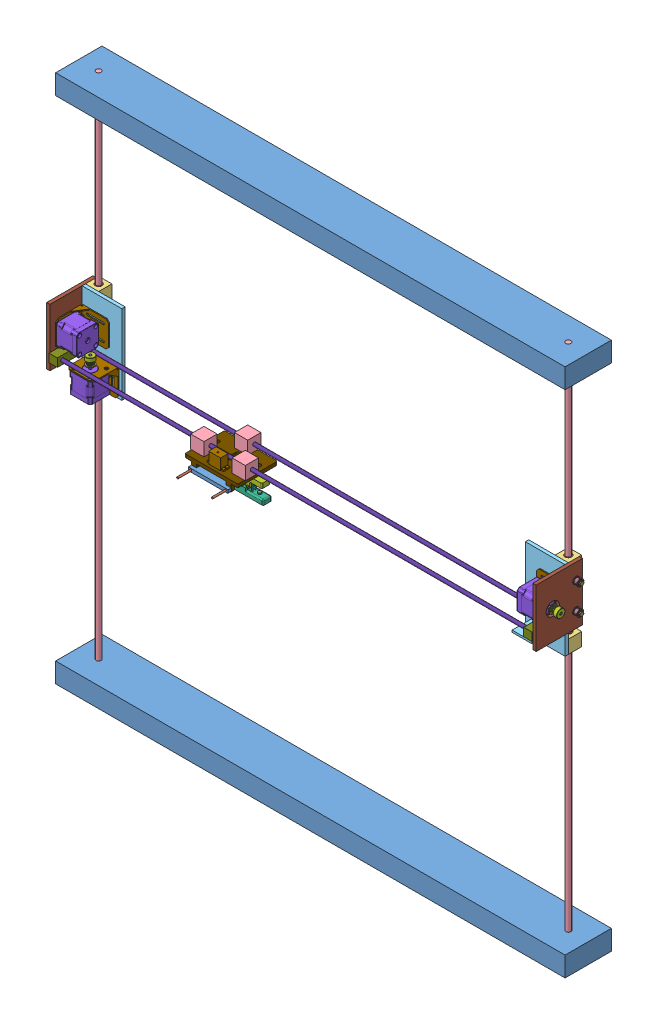
SolidWorks assembly Final Assembly, configuration Default. Lengths in mm.
Overall size (977.9 1016 174.63).
108 component instances, 28 part files, 72 mates.
Components (placement in the parent):
- Wood support-1: Wood support [Default] at (-151.6885 381.3846 556.984) size (977.9 38.1 88.9)
- Wood support-3: Wood support [Default] at (-151.6885 1397.3846 645.884) x (1 0 0) z (0 0 -1) size (977.9 38.1 88.9)
- Wood block w fitting-1: Wood block w fitting [Default] at (-133.7789 1054.3667 617.7695) x (0 0 -1) z (0 -1 0) size (25.4 25.4 25.4)
  - Bronze fitting-1: Bronze fitting [Default] at (16.3355 20.1904 11.168) size (12.7 12.7 25.4)
  - Wood block-1: Wood block [Default] at (3.6355 7.4904 11.168) size (25.4 25.4 25.4)
- Wood block w fitting-2: Wood block w fitting [Default] at (-133.7789 927.3667 617.7695) x (0 0 -1) z (0 -1 0) size (25.4 25.4 25.4)
  - Bronze fitting-1: Bronze fitting [Default] at (16.3355 20.1904 11.168) size (12.7 12.7 25.4)
  - Wood block-1: Wood block [Default] at (3.6355 7.4904 11.168) size (25.4 25.4 25.4)
- Wood block w fitting-3: Wood block w fitting [Default] at (808.3019 1054.3667 585.0985) x (0 0 1) z (0 -1 0) size (25.4 25.4 25.4)
  - Bronze fitting-1: Bronze fitting [Default] at (16.3355 20.1904 11.168) size (12.7 12.7 25.4)
  - Wood block-1: Wood block [Default] at (3.6355 7.4904 11.168) size (25.4 25.4 25.4)
- Wood block w fitting-4: Wood block w fitting [Default] at (808.3019 927.3667 585.0985) x (0 0 1) z (0 -1 0) size (25.4 25.4 25.4)
  - Bronze fitting-1: Bronze fitting [Default] at (16.3355 20.1904 11.168) size (12.7 12.7 25.4)
  - Wood block-1: Wood block [Default] at (3.6355 7.4904 11.168) size (25.4 25.4 25.4)
- Steel Rod-1: Steel Rod [Default] at (-113.5885 1397.3846 601.434) x (0.921856 0 -0.387532) z (0 -1 0) size (9.53 9.53 1016)
- Steel Rod-2: Steel Rod [Default] at (788.1115 1397.3846 601.434) x (-0.979084 0 0.203454) z (0 -1 0) size (9.53 9.53 1016)
- Support piece 2-1: Support piece 2 [Default] at (-88.1885 966.9987 614.134) x (0 -1 0) z (-1 0 0) size (152.4 6.35 76.2)
- Assem1-1: Assem1 [Default] at (-363.1535 858.375 468.4599) x (0 1 0) z (1 0 0) size (110.49 88.9 75.3)
  - Stepper Motor Assembly-1: Stepper Motor Assembly [Default] at (-2.6319 57.0939 61.9281) size (50 51.29 75.3)
    - Screw-1: Screw [Default] at (147.7106 140.4303 199.9369) x (-0.047434 -0.998874 0) z (0.998874 -0.047434 0) size (7 25.04 7)
    - GT2_Pulley20_Teeth.stp-1: GT2_Pulley20_Teeth.stp [Default] at (132.2106 125.0707 168.6369) x (-0.679392 0.733775 0) z (0 0 -1) size (16 16 16)
    - NEMA_17_Stepper_Motor.step-1: NEMA_17_Stepper_Motor.step [Default] at (136.9106 140.0707 -883.0631) size (42.3 42.3 63.3)
    - Nema17_Mounting_Bracket-1: Nema17_Mounting_Bracket [Default] at (157.2106 94.9303 174.9369) x (0 0 1) z (-1 0 0) size (53 51 50)
    - Screw-2: Screw [Default] at (116.7106 109.4303 199.8369) x (1 0 0) z (0 1 0) size (7 25.04 7)
    - Screw.step-2: Screw.step [Default] at (147.7106 109.4303 199.9369) x (1 0 0) z (0 1 0) size (7 25.04 7)
    - Screw.step-3: Screw.step [Default] at (116.7106 140.5707 199.9369) x (-1 0 0) z (0 -1 0) size (7 25.04 7)
  - Support Piece-1: Support Piece [Default] at (184.8237 213.7741 230.515) x (-1 0 0) z (0 1 0) size (110.49 6.35 88.9)
  - Hexagonal Bolt M4-25-1: Hexagonal Bolt M4-25 [Default] at (154.9787 137.5741 221.761) x (0 0 1) z (-0.984688 0.174326 0) size (22.54 7 8.08)
    - Hexagonal Bolt M4-25-1: Hexagonal Bolt M4-25 [Default] at origin size (28.05 7 8.08)
  - GT2_Pulley_No_Teeth.step-1: GT2_Pulley_No_Teeth.step [Default] at (153.5262 139.0817 213.265) x (-0.999997 0.002516 0) z (0 0 1) size (13 13 8.5)
  - GT2_Pulley_No_Teeth.step-2: GT2_Pulley_No_Teeth.step [Default] at (102.2066 138.2764 239.011) x (-0.414322 0.91013 0) z (0 0 -1) size (13 13 8.5)
  - Hexagonal Bolt M4-25-4: Hexagonal Bolt M4-25 [Default] at (104.1787 137.5741 221.507) x (0 0 1) z (-0.959769 0.280791 0) size (22.54 7 8.08)
    - Hexagonal Bolt M4-25-1: Hexagonal Bolt M4-25 [Default] at origin size (28.05 7 8.08)
  - Washer-1: Washer [Default] at (104.1787 137.5741 230.515) x (1 0 0) z (0 1 0) size (9.53 0.25 9.53)
  - Washer-2: Washer [Default] at (154.9787 137.5741 230.515) x (1 0 0) z (0 1 0) size (9.53 0.25 9.53)
  - Washer-3: Washer [Default] at (104.1787 137.5741 221.507) x (0.130919 0.991393 0) z (0.991393 -0.130919 0) size (9.53 0.25 9.53)
  - Washer-4: Washer [Default] at (154.9787 137.5741 221.761) x (0.849495 -0.527597 0) z (-0.527597 -0.849495 0) size (9.53 0.25 9.53)
  - Washer-5: Washer [Default] at (104.1787 137.5741 237.119) x (0.704272 0.70993 0) z (-0.70993 0.704272 0) size (9.53 0.25 9.53)
  - Washer-6: Washer [Default] at (154.9787 137.5741 237.119) x (1 0 0) z (0 1 0) size (9.53 0.25 9.53)
  - Hexagonal Nut M4-1: Hexagonal Nut M4 [Default] at (154.99 137.5786 237.119) x (0.949988 -0.312286 0) z (-0.312286 -0.949988 0) size (7 3.45 8.08)
    - Hexagonal Nut M4-1: Hexagonal Nut M4 [Default] x (0 -1 0) z (-1 0 0) size (3.45 8.08 7)
  - Hexagonal Nut M4-2: Hexagonal Nut M4 [Default] at (104.196 137.5251 237.119) x (0.955479 -0.29506 0) z (-0.29506 -0.955479 0) size (7 3.45 8.08)
    - Hexagonal Nut M4-1: Hexagonal Nut M4 [Default] x (0 -1 0) z (-1 0 0) size (3.45 8.08 7)
- Stepper Motor Assembly-1: Stepper Motor Assembly [Default] at (-212.6756 1118.7356 525.5537) x (1 0 0) z (0 -1 0) size (50 51.29 75.3)
  - Screw-1: Screw [Default] at (147.7106 140.4303 199.9369) x (-0.047434 -0.998874 0) z (0.998874 -0.047434 0) size (7 25.04 7)
  - GT2_Pulley20_Teeth.stp-1: GT2_Pulley20_Teeth.stp [Default] at (132.2106 125.0707 168.6369) x (-0.679392 0.733775 0) z (0 0 -1) size (16 16 16)
  - NEMA_17_Stepper_Motor.step-1: NEMA_17_Stepper_Motor.step [Default] at (136.9106 140.0707 -883.0631) size (42.3 42.3 63.3)
  - Nema17_Mounting_Bracket-1: Nema17_Mounting_Bracket [Default] at (157.2106 94.9303 174.9369) x (0 0 1) z (-1 0 0) size (53 51 50)
  - Screw-2: Screw [Default] at (116.7106 109.4303 199.8369) x (1 0 0) z (0 1 0) size (7 25.04 7)
  - Screw.step-2: Screw.step [Default] at (147.7106 109.4303 199.9369) x (1 0 0) z (0 1 0) size (7 25.04 7)
  - Screw.step-3: Screw.step [Default] at (116.7106 140.5707 199.9369) x (-1 0 0) z (0 -1 0) size (7 25.04 7)
- Assem1-2: Assem1 [Default] at (1037.6765 1117.5324 468.4599) x (0 -1 0) z (-1 0 0) size (110.49 88.9 75.3)
  - Stepper Motor Assembly-1: Stepper Motor Assembly [Default] at (-2.6319 57.0939 61.9281) size (50 51.29 75.3)
    - Screw-1: Screw [Default] at (147.7106 140.4303 199.9369) x (-0.047434 -0.998874 0) z (0.998874 -0.047434 0) size (7 25.04 7)
    - GT2_Pulley20_Teeth.stp-1: GT2_Pulley20_Teeth.stp [Default] at (132.2106 125.0707 168.6369) x (-0.679392 0.733775 0) z (0 0 -1) size (16 16 16)
    - NEMA_17_Stepper_Motor.step-1: NEMA_17_Stepper_Motor.step [Default] at (136.9106 140.0707 -883.0631) size (42.3 42.3 63.3)
    - Nema17_Mounting_Bracket-1: Nema17_Mounting_Bracket [Default] at (157.2106 94.9303 174.9369) x (0 0 1) z (-1 0 0) size (53 51 50)
    - Screw-2: Screw [Default] at (116.7106 109.4303 199.8369) x (1 0 0) z (0 1 0) size (7 25.04 7)
    - Screw.step-2: Screw.step [Default] at (147.7106 109.4303 199.9369) x (1 0 0) z (0 1 0) size (7 25.04 7)
    - Screw.step-3: Screw.step [Default] at (116.7106 140.5707 199.9369) x (-1 0 0) z (0 -1 0) size (7 25.04 7)
  - Support Piece-1: Support Piece [Default] at (184.8237 213.7741 230.515) x (-1 0 0) z (0 1 0) size (110.49 6.35 88.9)
  - Hexagonal Bolt M4-25-1: Hexagonal Bolt M4-25 [Default] at (154.9787 137.5741 221.761) x (0 0 1) z (-0.984688 0.174326 0) size (22.54 7 8.08)
    - Hexagonal Bolt M4-25-1: Hexagonal Bolt M4-25 [Default] at origin size (28.05 7 8.08)
  - GT2_Pulley_No_Teeth.step-1: GT2_Pulley_No_Teeth.step [Default] at (153.5262 139.0817 213.265) x (-0.999997 0.002516 0) z (0 0 1) size (13 13 8.5)
  - GT2_Pulley_No_Teeth.step-2: GT2_Pulley_No_Teeth.step [Default] at (102.2066 138.2764 239.011) x (-0.414322 0.91013 0) z (0 0 -1) size (13 13 8.5)
  - Hexagonal Bolt M4-25-4: Hexagonal Bolt M4-25 [Default] at (104.1787 137.5741 221.507) x (0 0 1) z (-0.959769 0.280791 0) size (22.54 7 8.08)
    - Hexagonal Bolt M4-25-1: Hexagonal Bolt M4-25 [Default] at origin size (28.05 7 8.08)
  - Washer-1: Washer [Default] at (104.1787 137.5741 230.515) x (1 0 0) z (0 1 0) size (9.53 0.25 9.53)
  - Washer-2: Washer [Default] at (154.9787 137.5741 230.515) x (1 0 0) z (0 1 0) size (9.53 0.25 9.53)
  - Washer-3: Washer [Default] at (104.1787 137.5741 221.507) x (0.130919 0.991393 0) z (0.991393 -0.130919 0) size (9.53 0.25 9.53)
  - Washer-4: Washer [Default] at (154.9787 137.5741 221.761) x (0.849495 -0.527597 0) z (-0.527597 -0.849495 0) size (9.53 0.25 9.53)
  - Washer-5: Washer [Default] at (104.1787 137.5741 237.119) x (0.704272 0.70993 0) z (-0.70993 0.704272 0) size (9.53 0.25 9.53)
  - Washer-6: Washer [Default] at (154.9787 137.5741 237.119) x (1 0 0) z (0 1 0) size (9.53 0.25 9.53)
  - Hexagonal Nut M4-1: Hexagonal Nut M4 [Default] at (154.99 137.5786 237.119) x (0.949988 -0.312286 0) z (-0.312286 -0.949988 0) size (7 3.45 8.08)
    - Hexagonal Nut M4-1: Hexagonal Nut M4 [Default] x (0 -1 0) z (-1 0 0) size (3.45 8.08 7)
  - Hexagonal Nut M4-2: Hexagonal Nut M4 [Default] at (104.196 137.5251 237.119) x (0.955479 -0.29506 0) z (-0.29506 -0.955479 0) size (7 3.45 8.08)
    - Hexagonal Nut M4-1: Hexagonal Nut M4 [Default] x (0 -1 0) z (-1 0 0) size (3.45 8.08 7)
- Support piece 2-2: Support piece 2 [Default] at (762.7115 966.9987 614.134) x (0 -1 0) z (-1 0 0) size (152.4 6.35 76.2)
- Wood block 2-1: Wood block 2 [Default] at (-118.351 955.0162 620.484) x (0 1 0) z (1 0 0) size (15.88 63.5 15.88)
- Wood block 2-2: Wood block 2 [Default] at (792.874 955.0162 620.484) x (0 -1 0) z (-1 0 0) size (15.88 63.5 15.88)
- Small Steel Rod-1: Small Steel Rod [Default] at (794.4615 955.0162 674.459) x (0 0.1575 0.987519) z (-1 0 0) size (6.35 6.35 914.4)
- Small Steel Rod-2: Small Steel Rod [Default] at (794.4615 955.0162 630.009) x (0 -0.084822 0.996396) z (-1 0 0) size (6.35 6.35 914.4)
- Drawing Mount Assembly-1: Drawing Mount Assembly [Default] at (161.5337 986.3363 732.2531) x (1 0 0) z (0 0 -1) size (101.6 22.23 107.95)
  - Drawing Mount-1: Drawing Mount [Default] at (39.6439 44.0201 83.1941) size (101.6 21.18 76.2)
  - Drawing mount 2-1: Drawing mount 2 [Default] at (39.7074 56.7201 62.1343) size (76.2 9.53 69.85)
  - 0.125 Dowel pin-1: 0.125 Dowel pin [Default] at (6.3064 59.8951 0.6441) x (0.801473 -0.598031 0) z (0 0 1) size (3.17 3.17 101.6)
  - 0.125 Dowel pin-2: 0.125 Dowel pin [Default] at (72.9814 59.8951 0.6441) x (0.816688 0.577079 0) z (0 0 1) size (3.17 3.17 101.6)
  - Spring-1: Spring [Default] at (6.3064 59.8951 38.9981) x (0.94588 -0.324516 0) z (-0.324516 -0.94588 0) size (3.43 38.61 3.96)
  - Spring-2: Spring [Default] at (72.9814 59.8951 38.9981) x (-0.31762 -0.948218 0) z (-0.948218 0.31762 0) size (3.43 38.61 3.96)
- Wood Support 3-1: Wood Support 3 [Default] at (161.524 955.0162 661.759) x (1 0 0) z (0 -1 0) size (25.4 25.4 31.75)
- Wood Support 3-2: Wood Support 3 [Default] at (240.978 955.0162 661.759) x (1 0 0) z (0 -1 0) size (25.4 25.4 31.75)
- Wood Support 3-3: Wood Support 3 [Default] at (201.1154 955.0162 617.309) x (1 0 0) z (0 -1 0) size (25.4 25.4 31.75)
- Pulley Support-1: Pulley Support [Default] at (760.8789 917.7735 618.5095) size (38.1 22.54 63.5)
  - Wood support 4-1: Wood support 4 [Default] at (1.8326 25.4952 65.4745) size (38.1 3.81 63.5)
  - Hexagonal Bolt M4-25-1: Hexagonal Bolt M4-25 [Default] at (21.0153 38.3132 36.8995) x (0 -1 0) z (-0.728918 0 0.684602) size (22.54 7 8.08)
    - Hexagonal Bolt M4-25-1: Hexagonal Bolt M4-25 [Default] at origin size (28.05 7 8.08)
  - Washer-1: Washer [Default] at (21.0153 38.3132 36.8995) x (-0.092668 0 -0.995697) z (-0.995697 0 0.092668) size (9.53 0.25 9.53)
  - Washer-2: Washer [Default] at (21.0153 25.2412 36.8995) x (-0.891041 0 -0.453923) z (0.453923 0 -0.891041) size (9.53 0.25 9.53)
  - Hexagonal Nut M4-1: Hexagonal Nut M4 [Default] at (21.0153 25.2412 36.8995) x (-0.955003 0 0.296596) z (0.296596 0 0.955003) size (7 3.45 8.08)
    - Hexagonal Nut M4-1: Hexagonal Nut M4 [Default] x (0 -1 0) z (-1 0 0) size (3.45 8.08 7)
  - GT2_Pulley_No_Teeth.step-1: GT2_Pulley_No_Teeth.step [Default] at (21.373 20.8092 34.8369) x (-0.588948 0 -0.808171) z (0 1 0) size (13 13 8.5)
  - Washer-3: Washer [Default] at (21.0153 29.3052 36.8995) x (-0.288637 0 0.957438) z (-0.957438 0 -0.288637) size (9.53 0.25 9.53)
- Clamp Assembly-1: Clamp Assembly [Default] at (188.3473 857.3342 582.5233) size (72.31 35.56 16.51)
  - Clamp 1-1: Clamp 1 [Default] at (-3.6913 33.5471 71.2954) size (69.85 21.59 16.51)
  - Clamp 2-1: Clamp 2 [Default] at (-6.1562 56.4071 54.7854) x (1 0 0) z (0 0 -1) size (69.85 21.59 16.51)
  - Clamp pin-1: Clamp pin [Default] at (36.5419 44.9771 54.7854) size (3.81 3.81 16.51)
- MG90S (1)-3: MG90S (1) [Défaut] at (213.4076 963.7162 694.409) x (-1 0 0) z (0 0 1) size (31.8 32.7 14.6)
- SM Arm-1: SM Arm [Default] at (206.1576 934.3162 687.159) x (-0.004706 0 0.999989) z (0 -1 0) size (7 22 7)
Mates (geometry in assembly coordinates):
- Concentric1: concentric anti-aligned: circle of Wood support-1; circle of Wood support-3
- Parallel1: parallel aligned: plane of Wood support-1 through (-151.6885 381.3846 645.884) normal (0 0 1); plane of Wood support-3 through (-151.6885 1397.3846 645.884) normal (0 0 1)
- Concentric4: concentric aligned: circle of Wood support-3; circle of Steel Rod-2
- Concentric5: concentric aligned: cylinder of Wood block w fitting-3/Bronze fitting-1 through (788.1115 1017.7987 601.434) axis (0 1 0) radius 4.7625; cylinder of Steel Rod-2 through (788.1115 381.3846 601.434) axis (0 1 0) radius 4.7625
- Concentric6: concentric aligned: cylinder of Wood block w fitting-4/Bronze fitting-1 through (788.1115 890.7987 601.434) axis (0 1 0) radius 4.7625; cylinder of Steel Rod-2 through (788.1115 381.3846 601.434) axis (0 1 0) radius 4.7625
- Concentric7: concentric aligned: circle of Wood support-3; circle of Steel Rod-1
- Concentric8: concentric aligned: cylinder of Wood block w fitting-1/Bronze fitting-1 through (-113.5885 1017.7987 601.434) axis (0 1 0) radius 4.7625; cylinder of Steel Rod-1 through (-113.5885 381.3846 601.434) axis (0 1 0) radius 4.7625
- Concentric9: concentric aligned: cylinder of Wood block w fitting-2/Bronze fitting-1 through (-113.5885 890.7987 601.434) axis (0 1 0) radius 4.7625; cylinder of Steel Rod-1 through (-113.5885 381.3846 601.434) axis (0 1 0) radius 4.7625
- Parallel8: parallel aligned: plane of Wood block w fitting-1/Wood block-1 through (-100.8885 1017.7987 614.134) normal (1 0 0); plane of Wood block w fitting-2/Wood block-1 through (-100.8885 890.7987 614.134) normal (1 0 0)
- Parallel9: parallel aligned: plane of Wood block w fitting-3/Wood block-1 through (775.4115 1017.7987 588.734) normal (-1 0 0); plane of Wood block w fitting-4/Wood block-1 through (775.4115 890.7987 588.734) normal (-1 0 0)
- Coincident27: coincident aligned: plane of Wood support-3 through (-151.6885 1397.3846 556.984) normal (0 1 0); plane of Steel Rod-2 through (788.1115 1397.3846 601.434) normal (0 1 0)
- Coincident28: coincident aligned: plane of Wood support-3 through (-151.6885 1397.3846 556.984) normal (0 1 0); plane of Steel Rod-1 through (-113.5885 1397.3846 601.434) normal (0 1 0)
- Coincident29: coincident aligned: plane of Wood support-1 through (-151.6885 381.3846 645.884) normal (0 -1 0); plane of Steel Rod-1 through (-113.5885 381.3846 601.434) normal (0 -1 0)
- Coincident31: coincident anti-aligned: plane of Wood block w fitting-1/Wood block-1 through (-126.2885 1017.7987 614.134) normal (0 0 1); plane of Support piece 2-1 through (-88.1885 966.9987 614.134) normal (0 0 -1)
- Coincident32: coincident anti-aligned: plane of Wood block w fitting-2/Wood block-1 through (-126.2885 890.7987 614.134) normal (0 0 1); plane of Support piece 2-1 through (-88.1885 966.9987 614.134) normal (0 0 -1)
- Coincident33: coincident aligned: line of Wood block w fitting-1/Wood block-1 through (-100.8885 1043.1987 614.134) axis (-1 0 0); line of Support piece 2-1 through (-50.0885 1043.1987 614.134) axis (-1 0 0)
- Parallel13: parallel aligned: line of Wood block w fitting-1/Wood block-1 through (-100.8885 1017.7987 614.134) axis (0 1 0); line of Support piece 2-1 through (-50.0885 890.7987 620.484) axis (0 1 0)
- Parallel14: parallel anti-aligned: line of Wood block w fitting-2/Wood block-1 through (-100.8885 890.7987 614.134) axis (-1 0 0); line of Support piece 2-1 through (-126.2885 890.7987 620.484) axis (1 0 0)
- Coincident36: coincident anti-aligned: line of Wood block w fitting-2/Wood block-1 through (-100.8885 890.7987 614.134) axis (-1 0 0); line of Support piece 2-1 through (-126.2885 890.7987 614.134) axis (1 0 0)
- Parallel18: parallel aligned: plane of Wood support-3 through (-151.6885 1397.3846 645.884) normal (0 0 1); plane of Support piece 2-1 through (-88.1885 966.9987 620.484) normal (0 0 1)
- Coincident49: coincident anti-aligned: plane of Support piece 2-1 through (-88.1885 966.9987 620.484) normal (0 0 1); plane of Assem1-1/Stepper Motor Assembly-1/Nema17_Mounting_Bracket-1 through (-73.2885 962.9537 620.484) normal (0 0 -1)
- Coincident51: coincident anti-aligned: plane of Support piece 2-1 through (-126.2885 890.7987 620.484) normal (-1 0 0); plane of Assem1-1/Support Piece-1 through (-126.2885 1043.1987 682.234) normal (1 0 0)
- Parallel19: parallel anti-aligned: plane of Support piece 2-1 through (-88.1885 966.9987 620.484) normal (0 0 1); plane of Stepper Motor Assembly-1/Nema17_Mounting_Bracket-1 through (-105.465 890.7987 620.484) normal (0 0 -1)
- Parallel20: parallel aligned: plane of Support piece 2-1 through (-126.2885 890.7987 620.484) normal (0 -1 0); plane of Stepper Motor Assembly-1/Nema17_Mounting_Bracket-1 through (-105.465 890.7987 622.484) normal (0 -1 0)
- Parallel21: parallel aligned: plane of Support piece 2-1 through (-126.2885 890.7987 620.484) normal (-1 0 0); plane of Stepper Motor Assembly-1/Nema17_Mounting_Bracket-1 through (-105.465 943.7987 620.484) normal (-1 0 0)
- Coincident56: coincident anti-aligned: plane of Support piece 2-1 through (-88.1885 966.9987 620.484) normal (0 0 1); plane of Stepper Motor Assembly-1/Nema17_Mounting_Bracket-1 through (-105.465 890.7987 620.484) normal (0 0 -1)
- Coincident57: coincident aligned: line of Support piece 2-1 through (-126.2885 890.7987 620.484) axis (1 0 0); line of Stepper Motor Assembly-1/Nema17_Mounting_Bracket-1 through (-100.465 890.7987 620.484) axis (1 0 0)
- Coincident58: coincident aligned: plane of Wood block w fitting-1/Wood block-1 through (-126.2885 1043.1987 614.134) normal (0 1 0); plane of Assem1-1/Support Piece-1 through (-126.2885 1043.1987 682.234) normal (0 1 0)
- Coincident59: coincident anti-aligned: line of Wood block w fitting-1/Wood block-1 through (-126.2885 1043.1987 614.134) axis (0 0 -1); line of Assem1-1/Support Piece-1 through (-126.2885 1043.1987 593.334) axis (0 0 1)
- Parallel22: parallel anti-aligned: plane of Wood block w fitting-3/Wood block-1 through (800.8115 1017.7987 614.134) normal (0 0 1); plane of Support piece 2-2 through (762.7115 966.9987 614.134) normal (0 0 -1)
- Coincident61: coincident anti-aligned: plane of Wood block w fitting-4/Wood block-1 through (800.8115 890.7987 614.134) normal (0 0 1); plane of Support piece 2-2 through (762.7115 966.9987 614.134) normal (0 0 -1)
- Coincident62: coincident anti-aligned: line of Wood block w fitting-4/Wood block-1 through (800.8115 890.7987 614.134) axis (-1 0 0); line of Support piece 2-2 through (724.6115 890.7987 614.134) axis (1 0 0)
- Coincident63: coincident aligned: line of Wood block w fitting-4/Wood block-1 through (800.8115 890.7987 614.134) axis (0 1 0); line of Support piece 2-2 through (800.8115 890.7987 614.134) axis (0 1 0)
- Coincident64: coincident aligned: line of Wood block w fitting-3/Wood block-1 through (800.8115 1043.1987 614.134) axis (-1 0 0); line of Support piece 2-2 through (800.8115 1043.1987 614.134) axis (-1 0 0)
- Parallel23: parallel aligned: plane of Wood support-3 through (-151.6885 1397.3846 645.884) normal (0 0 1); plane of Support piece 2-2 through (762.7115 966.9987 620.484) normal (0 0 1)
- Parallel24: parallel anti-aligned: plane of Wood block w fitting-3/Wood block-1 through (800.8115 1017.7987 588.734) normal (1 0 0); plane of Assem1-2/Support Piece-1 through (800.8115 932.7087 682.234) normal (-1 0 0)
- Coincident67: coincident anti-aligned: line of Wood block w fitting-3/Wood block-1 through (800.8115 1043.1987 588.734) axis (0 0 1); line of Assem1-2/Support Piece-1 through (800.8115 1043.1987 682.234) axis (0 0 -1)
- Coincident68: coincident anti-aligned: plane of Assem1-2/Stepper Motor Assembly-1/Nema17_Mounting_Bracket-1 through (747.8115 1012.9537 620.484) normal (0 0 -1); plane of Support piece 2-2 through (762.7115 966.9987 620.484) normal (0 0 1)
- Coincident71: coincident anti-aligned: plane of Support piece 2-1 through (-88.1885 966.9987 620.484) normal (0 0 1); plane of Wood block 2-1 through (-118.351 955.0162 620.484) normal (0 0 -1)
- Parallel25: parallel anti-aligned: plane of Assem1-1/Support Piece-1 through (-126.2885 1043.1987 682.234) normal (1 0 0); plane of Wood block 2-1 through (-126.2885 962.9537 683.984) normal (-1 0 0)
- Coincident73: coincident anti-aligned: plane of Assem1-1/Support Piece-1 through (-126.2885 1043.1987 682.234) normal (1 0 0); plane of Wood block 2-1 through (-126.2885 962.9537 683.984) normal (-1 0 0)
- Coincident74: coincident anti-aligned: plane of Assem1-1/Stepper Motor Assembly-1/Nema17_Mounting_Bracket-1 through (-126.2885 962.9537 620.484) normal (0 -1 0); plane of Wood block 2-1 through (-110.4135 962.9537 683.984) normal (0 1 0)
- Coincident75: coincident anti-aligned: plane of Assem1-2/Support Piece-1 through (800.8115 932.7087 682.234) normal (-1 0 0); plane of Wood block 2-2 through (800.8115 947.0787 683.984) normal (1 0 0)
- Coincident76: coincident anti-aligned: plane of Support piece 2-2 through (762.7115 966.9987 620.484) normal (0 0 1); plane of Wood block 2-2 through (792.874 955.0162 620.484) normal (0 0 -1)
- Coincident77: coincident anti-aligned: plane of Assem1-2/Stepper Motor Assembly-1/Nema17_Mounting_Bracket-1 through (800.8115 962.9537 620.484) normal (0 -1 0); plane of Wood block 2-2 through (784.9365 962.9537 683.984) normal (0 1 0)
- Concentric10: concentric aligned: circle of Wood block 2-2; circle of Small Steel Rod-1
- Coincident80: coincident anti-aligned: plane of Wood block 2-2 through (794.4615 955.0162 674.459) normal (-1 0 0); plane of Small Steel Rod-1 through (794.4615 955.0162 674.459) normal (1 0 0)
- Coincident81: coincident anti-aligned: plane of Wood block 2-1 through (-119.9385 955.0162 674.459) normal (1 0 0); plane of Small Steel Rod-1 through (-119.9385 955.0162 674.459) normal (-1 0 0)
- Concentric11: concentric anti-aligned: circle of Wood block 2-1; circle of Small Steel Rod-1
- Concentric12: concentric aligned: circle of Wood block 2-2; circle of Small Steel Rod-2
- Coincident84: coincident anti-aligned: plane of Wood block 2-2 through (794.4615 955.0162 630.009) normal (-1 0 0); plane of Small Steel Rod-2 through (794.4615 955.0162 630.009) normal (1 0 0)
- Concentric13: concentric aligned: cylinder of Small Steel Rod-1 through (-119.9385 955.0162 674.459) axis (1 0 0) radius 3.175; cylinder of Wood Support 3-1 through (148.824 955.0162 674.459) axis (1 0 0) radius 3.175
- Parallel26: parallel aligned: plane of Wood support-3 through (-151.6885 1397.3846 645.884) normal (0 0 1); plane of Wood Support 3-1 through (161.524 955.0162 687.159) normal (0 0 1)
- Concentric14: concentric aligned: circle of Drawing Mount Assembly-1/Drawing Mount-1; circle of Wood Support 3-1
- Coincident89: coincident aligned: plane of Drawing Mount Assembly-1/Drawing Mount-1 through (201.1776 935.9662 649.059) normal (0 -1 0); plane of Wood Support 3-1 through (161.524 935.9662 674.459) normal (0 -1 0)
- Concentric15: concentric aligned: cylinder of Small Steel Rod-1 through (-119.9385 955.0162 674.459) axis (1 0 0) radius 3.175; cylinder of Wood Support 3-2 through (228.278 955.0162 674.459) axis (1 0 0) radius 3.175
- Parallel27: parallel aligned: plane of Wood support-3 through (-151.6885 1397.3846 645.884) normal (0 0 1); plane of Wood Support 3-2 through (240.978 955.0162 687.159) normal (0 0 1)
- Concentric16: concentric aligned: cylinder of Drawing Mount Assembly-1/Drawing Mount-1 through (240.978 935.9662 674.459) axis (0 1 0) radius 3.175; cylinder of Wood Support 3-2 through (240.978 935.9662 674.459) axis (0 1 0) radius 3.175
- Concentric17: concentric aligned: axis of Small Steel Rod-2 through (-119.9385 955.0162 630.009) axis (1 0 0); cylinder of Wood Support 3-3 through (188.4154 955.0162 630.009) axis (1 0 0) radius 3.175
- Parallel29: parallel aligned: plane of Wood support-3 through (-151.6885 1397.3846 556.984) normal (0 0 -1); plane of Wood Support 3-3 through (201.1154 955.0162 617.309) normal (0 0 -1)
- Concentric18: concentric aligned: cylinder of Drawing Mount Assembly-1/Drawing Mount-1 through (201.1154 935.9662 630.009) axis (0 1 0) radius 3.175; cylinder of Wood Support 3-3 through (201.1154 935.9662 630.009) axis (0 1 0) radius 3.175
- Coincident108: coincident anti-aligned: plane of Assem1-2/Support Piece-1 through (800.8115 932.7087 682.234) normal (-1 0 0); plane of Pulley Support-1/Wood support 4-1 through (800.8115 947.0787 683.984) normal (1 0 0)
- Coincident109: coincident anti-aligned: plane of Support piece 2-2 through (762.7115 966.9987 620.484) normal (0 0 1); plane of Pulley Support-1/Wood support 4-1 through (762.7115 947.0787 620.484) normal (0 0 -1)
- Coincident110: coincident anti-aligned: plane of Wood block 2-2 through (784.9365 947.0787 683.984) normal (0 -1 0); plane of Pulley Support-1/Wood support 4-1 through (762.7115 947.0787 683.984) normal (0 1 0)
- Concentric25: concentric aligned: circle of Drawing Mount Assembly-1/Drawing mount 2-1; circle of Clamp Assembly-1/Clamp 2-1
- Coincident129: coincident anti-aligned: plane of Drawing Mount Assembly-1/Drawing mount 2-1 through (201.2411 920.0912 645.5637) normal (0 -1 0); plane of Clamp Assembly-1/Clamp 2-1 through (182.1911 920.0912 637.3087) normal (0 1 0)
- Parallel43: parallel aligned: plane of Drawing Mount Assembly-1/Drawing Mount-1 through (201.1776 935.9662 699.859) normal (0 0 1); plane of Clamp Assembly-1/Clamp 2-1 through (182.1911 907.3912 653.8187) normal (0 0 1)
- Parallel47: parallel aligned: plane of Drawing Mount Assembly-1/Drawing Mount-1 through (201.1776 935.9662 699.859) normal (0 0 1); plane of MG90S (1)-3 through (213.4076 940.3162 694.409) normal (0 0 1)
- Concentric28: concentric anti-aligned: circle of Drawing Mount Assembly-1/Drawing Mount-1; circle of MG90S (1)-3
- Coincident137: coincident anti-aligned: plane of Drawing Mount Assembly-1/Drawing Mount-1 through (201.1776 942.3162 649.059) normal (0 1 0); plane of MG90S (1)-3 through (213.4076 942.3162 694.409) normal (0 -1 0)
- Concentric29: concentric anti-aligned: circle of MG90S (1)-3; circle of SM Arm-1
- Coincident138: coincident anti-aligned: plane of MG90S (1)-3 through (206.1576 934.3162 687.159) normal (0 -1 0); plane of SM Arm-1 through (198.6577 934.3162 687.1237) normal (0 1 0)
